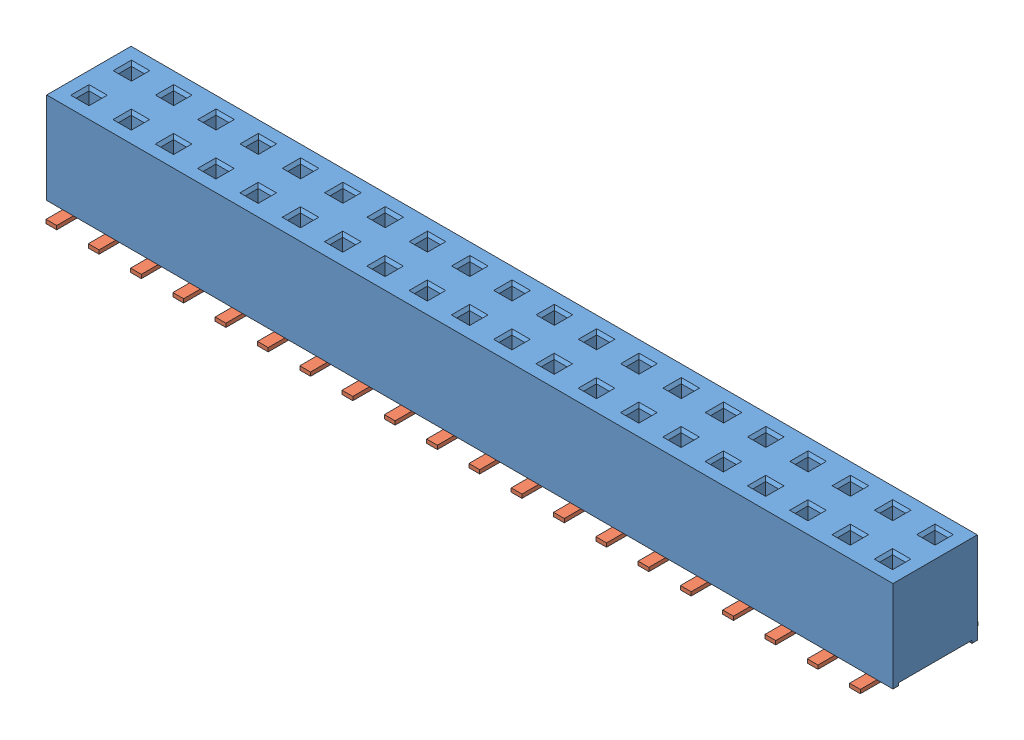
SolidWorks assembly felame_header_SMD, configuration Default. Lengths in mm.
Overall size (40 4.5 5.56).
3 component instances, 2 part files, 0 mates.
Components (placement in the parent):
- TLE-120-01-G-DV 40 pin low speed connector-1: TLE-120-01-G-DV 40 pin low speed connector [Default] at (-13.5653 1.7778 -22.9939) size (40 4.5 5.56)
  - _TLE-120-01-DV_socket-1: _TLE-120-01-DV_socket [Default] at origin size (40 4.32 3.99)
  - _C-101-01-20-1: _C-101-01-20 [Default] at origin size (39.47 3.51 5.56)
